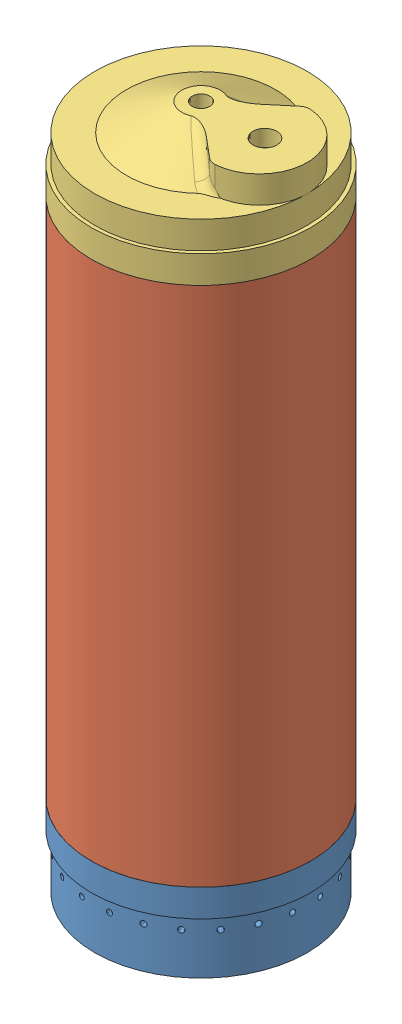
SolidWorks assembly LOX_TankV2, configuration Default. Lengths in mm.
Overall size (264.78 633.57 264.78).
4 component instances, 4 part files, 10 mates.
Components (placement in the parent):
- IT-U-Bulkhead-1: IT-U-Bulkhead [Default] at (-37.5444 37.5444 0) x (0 0 -1) z (-1 0 0) size (203.2 75.09 203.2)
- LOXTankCylinder-1: LOXTankCylinder [Default] at (0 557.6887 0) x (0 -1 0) z (0.302469 0 0.953159) size (482.6 203.2 203.2)
- UT-T-Bulkhead_V5-1: UT-T-Bulkhead_V5 [Default] at (0 595.63 37.9413) size (203.2 75.88 203.2)
- Arbitrary LOX in LOX Tank-1: Arbitrary LOX in LOX Tank [Default] at (0 75.0887 0) x (0.825464 0 0.564455) z (-0.564455 0 0.825464) size (190.5 541.78 190.5)
Mates (geometry in assembly coordinates):
- Concentric4: concentric anti-aligned: circle of IT-U-Bulkhead-1; circle of LOXTankCylinder-1
- Coincident14: coincident anti-aligned: plane of IT-U-Bulkhead-1 through (0 75.0887 0) normal (0 1 0); plane of LOXTankCylinder-1 through (0 75.0887 0) normal (0 -1 0)
- Concentric5: concentric aligned: cylinder of IT-U-Bulkhead-1 through (0 75.0887 0) axis (0 1 0) radius 8.0962
- Coincident15: coincident anti-aligned: plane of IT-U-Bulkhead-1 through (0 0 0) normal (0 -1 0)
- Concentric6: concentric anti-aligned: cylinder of LOXTankCylinder-1 through (0 75.0887 0) axis (0 1 0) radius 101.6; cylinder of UT-T-Bulkhead_V5-1 through (0 557.6887 0) axis (0 -1 0) radius 101.6
- Coincident16: coincident anti-aligned: plane of LOXTankCylinder-1 through (0 557.6887 0) normal (0 1 0); plane of UT-T-Bulkhead_V5-1 through (0 557.6887 0) normal (0 -1 0)
- Coincident17: coincident anti-aligned: plane of IT-U-Bulkhead-1 through (-37.5444 37.5444 0) normal (0 0 -1)
- Parallel1: parallel aligned: plane of UT-T-Bulkhead_V5-1 through (0 595.63 37.9413) normal (0 0 1)
- Concentric7: concentric anti-aligned: cylinder of LOXTankCylinder-1 through (0 75.0887 0) axis (0 1 0) radius 95.25; cylinder of Arbitrary LOX in LOX Tank-1 through (0 557.6887 0) axis (0 -1 0) radius 95.25
- Coincident18: coincident aligned: circle of LOXTankCylinder-1; circle of Arbitrary LOX in LOX Tank-1
